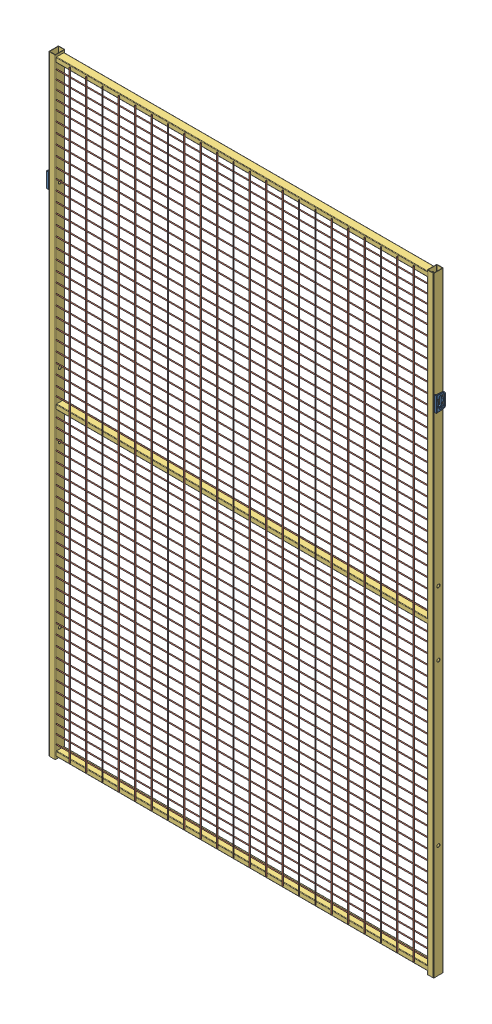
SolidWorks assembly W322-190120-Axelent, configuration Default. Lengths in mm.
Overall size (1215.63 1900 30).
4 component instances, 3 part files, 0 mates.
Components (placement in the parent):
- G2032-1: G2032 [Default] at (-599 600 0) size (9.31 48.01 29.42)
- G2032-2: G2032 [Default] at (599 600 0) x (-1 0 0) z (0 0 1) size (9.31 48.01 29.42)
- NÄT-50x30_II_N-05030-190-120-1: NÄT-50x30_II_N-05030-190-120 [Default] at (0 0 13.5) x (-1 0 0) z (0 0 -1) size (1180 1876 4.75)
- RAM-30_RAM-190-120-1: RAM-30_RAM-190-120 [Default] at origin size (1198 1900 30)
